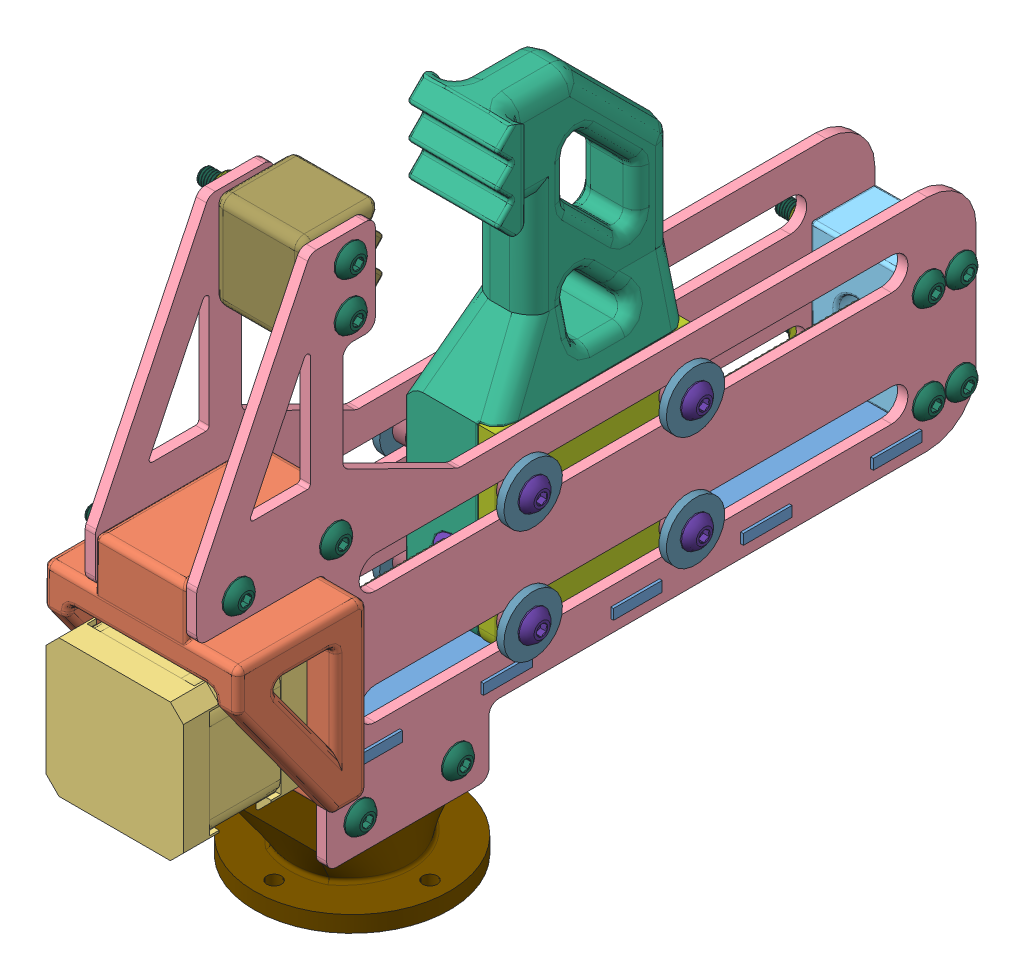
SolidWorks assembly UOM20-4A005, configuration Default. Lengths in mm.
Overall size (60 183.76 249.79).
68 component instances, 20 part files, 130 mates.
Components (placement in the parent):
- UOM20-4P007-1: UOM20-4P007 [Default] at (-2.435 1.3419 -83.2582) x (1 0 0) z (0 1 0) size (36 187.5 3.17)
- UOM20-4P033-1: UOM20-4P033 [Default] at (52.6461 0.8419 41.1062) x (-1 0 0) z (0 0 -1) size (60 68.5 50)
- Stepper with LeadScrew-1: Stepper with LeadScrew [Default] at (22.6461 22.5919 19.1062) x (1 0 0) z (0 1 0) size (42.3 239.5 42.3)
- UOM20-4P009-1: UOM20-4P009 [Default] at (39.8211 157.3419 -13.967) x (0 0 -1) z (1 0 0) size (240 167.68 3.17)
- UOM20-4P009-2: UOM20-4P009 [Default] at (8.6461 157.3419 -13.967) x (0 0 -1) z (1 0 0) size (240 167.68 3.17)
- UOM20-4P012-1: UOM20-4P012 [Default] at (8.6461 2.5919 -198.967) size (28 40 20)
- UOM20-4A006-1: UOM20-4A006 [Default] at (-25.0544 -2.4389 -59.9519) x (0 0 -1) z (1 0 0) size (60.07 140.34 28.19)
  - UOM20-4P011-1: UOM20-4P011 [Default] at (-5.5057 4.0308 33.7005) size (60.07 140.34 28.19)
  - UOM20-4P036-1: UOM20-4P036 [Default] at (54.4943 4.0308 61.7005) x (-1 0 0) z (0 0 -1) size (60 60 6)
  - 6659K676_OIL-EMBEDDED FLANGED SLEEVE BEARING-1: 6659K676_OIL-EMBEDDED FLANGED SLEEVE BEARING [6659K676] at (4.4943 25.0308 47.7005) x (0 -0.441612 0.897206) z (0 -0.897206 -0.441612) size (14 10 14)
  - 6659K676_OIL-EMBEDDED FLANGED SLEEVE BEARING-2: 6659K676_OIL-EMBEDDED FLANGED SLEEVE BEARING [6659K676] at (44.4943 25.0308 47.7005) x (0 -0.999819 0.019038) z (0 0.019038 0.999819) size (14 10 14)
  - 9434K135_MUSIC-WIRE STEEL COMPRESSION SPRINGS-1: 9434K135_MUSIC-WIRE STEEL COMPRESSION SPRINGS [9434K135] at (36.2443 25.1246 46.92) x (0 1 0) z (0 0 1) size (15.72 32.66 15.84)
  - leadnut-1: leadnut [Default] at (35.2443 25.0308 47.7005) x (1 0 0) z (0 0 -1) size (10 24 10.5)
  - UOM20-4P038-1: UOM20-4P038 [Default] at (43.2443 38.0308 55.7005) x (0 0 -1) z (-1 0 0) size (16 26 7)
- UOM20-4P008-1: UOM20-4P008 [Default] at (8.6461 111.8419 4.7646) x (0 0 -1) z (1 0 0) size (24.59 30 28)
- 94669A071_ALUM UNTHRD SPACER-1: 94669A071_ALUM UNTHRD SPACER [94669A071] at (38.6461 11.5919 -59.4462) x (0 0.521387 0.85332) z (1 0 0) size (10 10 4)
- 98363A111_ STEEL OVERSIZED WASHER-1: 98363A111_ STEEL OVERSIZED WASHER [98363A111] at (42.9461 11.5919 -59.4462) x (0 0.435821 0.900034) z (-1 0 0) size (18 18 2.3)
- 94669A071_ALUM UNTHRD SPACER-4: 94669A071_ALUM UNTHRD SPACER [94669A071] at (6.6461 11.5919 -59.4462) x (0 0.783153 0.621829) z (-1 0 0) size (10 10 4)
- 94669A071_ALUM UNTHRD SPACER-5: 94669A071_ALUM UNTHRD SPACER [94669A071] at (38.6461 46.5919 -109.4462) x (0 0.783153 0.621829) z (-1 0 0) size (10 10 4)
- 94669A071_ALUM UNTHRD SPACER-6: 94669A071_ALUM UNTHRD SPACER [94669A071] at (6.6461 46.5919 -59.4462) x (0 0.783153 0.621829) z (-1 0 0) size (10 10 4)
- 94669A071_ALUM UNTHRD SPACER-7: 94669A071_ALUM UNTHRD SPACER [94669A071] at (38.6461 11.5919 -109.4462) x (0 0.783153 0.621829) z (-1 0 0) size (10 10 4)
- 94669A071_ALUM UNTHRD SPACER-8: 94669A071_ALUM UNTHRD SPACER [94669A071] at (6.6461 11.5919 -109.4462) x (0 0.783153 0.621829) z (-1 0 0) size (10 10 4)
- 94669A071_ALUM UNTHRD SPACER-9: 94669A071_ALUM UNTHRD SPACER [94669A071] at (6.6461 46.5919 -109.4462) x (0 -0.340925 0.94009) z (-1 0 0) size (10 10 4)
- 94669A071_ALUM UNTHRD SPACER-10: 94669A071_ALUM UNTHRD SPACER [94669A071] at (38.6461 46.5919 -59.4462) x (0 0.783153 0.621829) z (-1 0 0) size (10 10 4)
- 98363A111_ STEEL OVERSIZED WASHER-2: 98363A111_ STEEL OVERSIZED WASHER [98363A111] at (42.9461 46.5919 -59.4462) x (0 0.435821 0.900034) z (-1 0 0) size (18 18 2.3)
- 98363A111_ STEEL OVERSIZED WASHER-3: 98363A111_ STEEL OVERSIZED WASHER [98363A111] at (42.9461 46.5919 -109.4462) x (0 0.435821 0.900034) z (-1 0 0) size (18 18 2.3)
- 98363A111_ STEEL OVERSIZED WASHER-4: 98363A111_ STEEL OVERSIZED WASHER [98363A111] at (42.9461 11.5919 -109.4462) x (0 0.603887 0.79707) z (-1 0 0) size (18 18 2.3)
- 98363A111_ STEEL OVERSIZED WASHER-5: 98363A111_ STEEL OVERSIZED WASHER [98363A111] at (4.6461 46.5919 -59.4462) x (0 0.435821 0.900034) z (-1 0 0) size (18 18 2.3)
- 98363A111_ STEEL OVERSIZED WASHER-6: 98363A111_ STEEL OVERSIZED WASHER [98363A111] at (4.6461 11.5919 -59.4462) x (0 0.435821 0.900034) z (-1 0 0) size (18 18 2.3)
- 98363A111_ STEEL OVERSIZED WASHER-7: 98363A111_ STEEL OVERSIZED WASHER [98363A111] at (4.6461 11.5919 -109.4462) x (0 0.756126 0.654426) z (-1 0 0) size (18 18 2.3)
- 98363A111_ STEEL OVERSIZED WASHER-8: 98363A111_ STEEL OVERSIZED WASHER [98363A111] at (4.6461 46.5919 -109.4462) x (0 0.435821 0.900034) z (-1 0 0) size (18 18 2.3)
- 92095A223_BUTTON HEAD HEX DRIVE SCREW (1)-1: 92095A223_BUTTON HEAD HEX DRIVE SCREW (1) [92095A223] at (42.5711 37.5919 -193.967) x (0 0.716827 -0.697251) z (1 0 0) size (9.5 9.5 48.41)
- 92095A223_BUTTON HEAD HEX DRIVE SCREW (1)-2: 92095A223_BUTTON HEAD HEX DRIVE SCREW (1) [92095A223] at (42.5711 37.5919 -183.967) x (0 0.158553 -0.987351) z (1 0 0) size (9.5 9.5 48.41)
- 92095A223_BUTTON HEAD HEX DRIVE SCREW (1)-3: 92095A223_BUTTON HEAD HEX DRIVE SCREW (1) [92095A223] at (42.5711 7.5919 -183.967) x (0 0.282984 -0.959125) z (1 0 0) size (9.5 9.5 48.41)
- 92095A223_BUTTON HEAD HEX DRIVE SCREW (1)-4: 92095A223_BUTTON HEAD HEX DRIVE SCREW (1) [92095A223] at (42.5711 7.5919 -193.967) x (0 0.371154 -0.928571) z (1 0 0) size (9.5 9.5 48.41)
- 93625A200_18-8 STAINLESS STEEL NYLON-INSERT LOCKNUT-14: 93625A200_18-8 STAINLESS STEEL NYLON-INSERT LOCKNUT [93625A200] at (2.9711 37.5919 -183.967) x (0 1 0) z (0 0 1) size (8 5.02 9.24)
- 93625A200_18-8 STAINLESS STEEL NYLON-INSERT LOCKNUT-17: 93625A200_18-8 STAINLESS STEEL NYLON-INSERT LOCKNUT [93625A200] at (2.9711 37.5919 -193.967) x (0 0.266649 0.963794) z (0 -0.963794 0.266649) size (8 5.02 9.24)
- 93625A200_18-8 STAINLESS STEEL NYLON-INSERT LOCKNUT-15: 93625A200_18-8 STAINLESS STEEL NYLON-INSERT LOCKNUT [93625A200] at (2.9711 7.5919 -183.967) x (0 -0.998058 -0.062298) z (0 0.062298 -0.998058) size (8 5.02 9.24)
- 93625A200_18-8 STAINLESS STEEL NYLON-INSERT LOCKNUT-23: 93625A200_18-8 STAINLESS STEEL NYLON-INSERT LOCKNUT [93625A200] at (2.9711 7.5919 -193.967) x (0 -0.998058 -0.062298) z (0 0.062298 -0.998058) size (8 5.02 9.24)
- 92095A223_BUTTON HEAD HEX DRIVE SCREW (1)-6: 92095A223_BUTTON HEAD HEX DRIVE SCREW (1) [92095A223] at (42.5711 119.3419 -5.967) x (0 0.158553 -0.987351) z (1 0 0) size (9.5 9.5 48.41)
- 92095A223_BUTTON HEAD HEX DRIVE SCREW (1)-8: 92095A223_BUTTON HEAD HEX DRIVE SCREW (1) [92095A223] at (42.5711 61.8419 -1.467) x (0 0.125077 -0.992147) z (1 0 0) size (9.5 9.5 48.41)
- 92095A223_BUTTON HEAD HEX DRIVE SCREW (1)-9: 92095A223_BUTTON HEAD HEX DRIVE SCREW (1) [92095A223] at (42.5711 134.3419 -5.967) x (0 0.431476 -0.902124) z (1 0 0) size (9.5 9.5 48.41)
- 92095A223_BUTTON HEAD HEX DRIVE SCREW (1)-10: 92095A223_BUTTON HEAD HEX DRIVE SCREW (1) [92095A223] at (42.5711 61.8419 28.533) x (0 0.513686 -0.857978) z (1 0 0) size (9.5 9.5 48.41)
- 92095A223_BUTTON HEAD HEX DRIVE SCREW (1)-11: 92095A223_BUTTON HEAD HEX DRIVE SCREW (1) [92095A223] at (42.5711 -15.8331 -38.967) x (0 0.559632 -0.828741) z (1 0 0) size (9.5 9.5 48.41)
- 92095A223_BUTTON HEAD HEX DRIVE SCREW (1)-13: 92095A223_BUTTON HEAD HEX DRIVE SCREW (1) [92095A223] at (42.5711 -15.8331 -8.967) x (0 0.683952 -0.729527) z (1 0 0) size (9.5 9.5 48.41)
- 93625A200_18-8 STAINLESS STEEL NYLON-INSERT LOCKNUT-20: 93625A200_18-8 STAINLESS STEEL NYLON-INSERT LOCKNUT [93625A200] at (2.9711 61.8419 28.533) x (0 0.266649 0.963794) z (0 -0.963794 0.266649) size (8 5.02 9.24)
- 93625A200_18-8 STAINLESS STEEL NYLON-INSERT LOCKNUT-16: 93625A200_18-8 STAINLESS STEEL NYLON-INSERT LOCKNUT [93625A200] at (2.9711 -15.8331 -8.967) x (0 0.110464 0.99388) z (0 -0.99388 0.110464) size (8 5.02 9.24)
- 93625A200_18-8 STAINLESS STEEL NYLON-INSERT LOCKNUT-24: 93625A200_18-8 STAINLESS STEEL NYLON-INSERT LOCKNUT [93625A200] at (2.9711 134.3419 -5.967) x (0 -0.016988 0.999856) z (0 -0.999856 -0.016988) size (8 5.02 9.24)
- 93625A200_18-8 STAINLESS STEEL NYLON-INSERT LOCKNUT-18: 93625A200_18-8 STAINLESS STEEL NYLON-INSERT LOCKNUT [93625A200] at (2.9711 -15.8331 -38.967) x (0 -0.311672 0.95019) z (0 -0.95019 -0.311672) size (8 5.02 9.24)
- 93625A200_18-8 STAINLESS STEEL NYLON-INSERT LOCKNUT-25: 93625A200_18-8 STAINLESS STEEL NYLON-INSERT LOCKNUT [93625A200] at (2.9711 61.8419 -1.467) x (0 0.201211 -0.979548) z (0 0.979548 0.201211) size (8 5.02 9.24)
- 93625A200_18-8 STAINLESS STEEL NYLON-INSERT LOCKNUT-26: 93625A200_18-8 STAINLESS STEEL NYLON-INSERT LOCKNUT [93625A200] at (2.9711 119.3419 -5.967) x (0 -0.173645 0.984808) z (0 -0.984808 -0.173645) size (8 5.02 9.24)
- 93625A200_18-8 STAINLESS STEEL NYLON-INSERT LOCKNUT-19: 93625A200_18-8 STAINLESS STEEL NYLON-INSERT LOCKNUT [93625A200] at (-0.1539 11.5919 -109.4462) x (0 -0.311672 0.95019) z (0 -0.95019 -0.311672) size (8 5.02 9.24)
- 93625A200_18-8 STAINLESS STEEL NYLON-INSERT LOCKNUT-13: 93625A200_18-8 STAINLESS STEEL NYLON-INSERT LOCKNUT [93625A200] at (-0.1539 11.5919 -59.4462) x (0 -0.458385 0.888754) z (0 -0.888754 -0.458385) size (8 5.02 9.24)
- 93625A200_18-8 STAINLESS STEEL NYLON-INSERT LOCKNUT-21: 93625A200_18-8 STAINLESS STEEL NYLON-INSERT LOCKNUT [93625A200] at (-0.1539 46.5919 -109.4462) x (0 -0.56782 0.823153) z (0 -0.823153 -0.56782) size (8 5.02 9.24)
- 93625A200_18-8 STAINLESS STEEL NYLON-INSERT LOCKNUT-22: 93625A200_18-8 STAINLESS STEEL NYLON-INSERT LOCKNUT [93625A200] at (-0.1539 46.5919 -59.4462) x (0 -0.642076 0.766641) z (0 -0.766641 -0.642076) size (8 5.02 9.24)
- 92095A228_BUTTON HEAD HEX DRIVE SCREW-1: 92095A228_BUTTON HEAD HEX DRIVE SCREW [92095A228] at (45.6961 11.5919 -59.4462) x (0 -0.924225 -0.381849) z (1 0 0) size (9.5 9.5 53.02)
- 92095A228_BUTTON HEAD HEX DRIVE SCREW-2: 92095A228_BUTTON HEAD HEX DRIVE SCREW [92095A228] at (45.6961 46.5919 -59.4462) x (0 0 -1) z (1 0 0) size (9.5 9.5 53.02)
- 92095A228_BUTTON HEAD HEX DRIVE SCREW-3: 92095A228_BUTTON HEAD HEX DRIVE SCREW [92095A228] at (45.6961 46.5919 -109.4462) x (0 0 -1) z (1 0 0) size (9.5 9.5 53.02)
- 92095A228_BUTTON HEAD HEX DRIVE SCREW-4: 92095A228_BUTTON HEAD HEX DRIVE SCREW [92095A228] at (45.6961 11.5919 -109.4462) x (0 0 -1) z (1 0 0) size (9.5 9.5 53.02)
- UOM20-4P013-2: UOM20-4P013 [Default] at (22.6461 -36.8331 -23.967) x (0 0 1) z (0 1 0) size (60 60 40)
- 92855A313_TYPE 18-8 SS LOW PROFILE SOCKET CAP SCREW-1: 92855A313_TYPE 18-8 SS LOW PROFILE SOCKET CAP SCREW [92855A313] at (38.1461 38.0919 15.5062) size (5.5 5.5 14.55)
- 98689A112_ METRIC GENERAL PURPOSE WASHERS (1)-1: 98689A112_ METRIC GENERAL PURPOSE WASHERS (1) [98689A112] at (38.1461 38.0919 4.1062) x (-0.923728 -0.383049 0) z (0 0 -1) size (6 6 0.6)
- 98689A112_ METRIC GENERAL PURPOSE WASHERS (1)-2: 98689A112_ METRIC GENERAL PURPOSE WASHERS (1) [98689A112] at (38.1461 7.0919 4.1062) x (-0.85131 -0.524663 0) z (0 0 -1) size (6 6 0.6)
- 98689A112_ METRIC GENERAL PURPOSE WASHERS (1)-4: 98689A112_ METRIC GENERAL PURPOSE WASHERS (1) [98689A112] at (7.1461 7.0919 4.1062) x (-0.777574 -0.628792 0) z (0 0 -1) size (6 6 0.6)
- 98689A112_ METRIC GENERAL PURPOSE WASHERS (1)-6: 98689A112_ METRIC GENERAL PURPOSE WASHERS (1) [98689A112] at (7.1461 38.0919 4.1062) x (-0.715577 -0.698533 0) z (0 0 -1) size (6 6 0.6)
- 92855A313_TYPE 18-8 SS LOW PROFILE SOCKET CAP SCREW-3: 92855A313_TYPE 18-8 SS LOW PROFILE SOCKET CAP SCREW [92855A313] at (38.1461 7.0919 15.5062) x (0.216826 -0.97621 0) z (0 0 1) size (5.5 5.5 14.55)
- 92855A313_TYPE 18-8 SS LOW PROFILE SOCKET CAP SCREW-5: 92855A313_TYPE 18-8 SS LOW PROFILE SOCKET CAP SCREW [92855A313] at (7.1461 7.0919 15.5062) x (0.044015 -0.999031 0) z (0 0 1) size (5.5 5.5 14.55)
- 92855A313_TYPE 18-8 SS LOW PROFILE SOCKET CAP SCREW-7: 92855A313_TYPE 18-8 SS LOW PROFILE SOCKET CAP SCREW [92855A313] at (7.1461 38.0919 15.5062) x (-0.130134 -0.991496 0) z (0 0 1) size (5.5 5.5 14.55)
Mates (geometry in assembly coordinates):
- Concentric3: concentric anti-aligned: circle of Part4-1; circle of Stepper with LeadScrew-1
- Coincident3: coincident anti-aligned: plane of Part4-1 through (52.6461 0.8419 11.1062) normal (0 0 1); plane of Stepper with LeadScrew-1 through (22.6461 22.5919 11.1062) normal (0 0 -1)
- Parallel1: parallel aligned: plane of Part4-1 through (-7.3539 40.8419 1.1062) normal (-1 0 0); plane of Stepper with LeadScrew-1 through (1.5461 37.4919 41.1062) normal (-1 0 0)
- Parallel2: parallel anti-aligned: plane of Part1-1 through (-2.435 -1.8331 -83.2582) normal (0 -1 0); plane of Part4-1 through (8.6461 69.3419 41.033) normal (0 1 0)
- Coincident7: coincident aligned: plane of Part1-1 through (8.6461 -8.6581 18.533) normal (-1 0 0); plane of Part4-1 through (8.6461 0.8419 41.1062) normal (-1 0 0)
- Coincident8: coincident anti-aligned: plane of UOM20-4P031-1 through (40.6461 -8.6581 -6.467) normal (0 0 1); plane of UOM20-4P032-1 through (36.6461 -1.8331 -6.467) normal (0 0 -1)
- Coincident9: coincident anti-aligned: plane of Part2-1 through (36.6461 157.3419 -13.967) normal (-1 0 0); plane of Part4-1 through (36.6461 0.8419 41.1062) normal (1 0 0)
- Coincident10: coincident anti-aligned: plane of Part1-1 through (-2.435 1.3419 -83.2582) normal (0 1 0); plane of Part2-1 through (36.6461 1.3419 -101.467) normal (0 -1 0)
- Coincident19: coincident anti-aligned: plane of Part4-1 through (-7.3539 54.3419 1.1062) normal (0 1 0); plane of Part2-1 through (36.6461 54.3419 41.033) normal (0 -1 0)
- Coincident24: coincident anti-aligned: plane of Part4-1 through (8.6461 0.8419 41.1062) normal (-1 0 0); plane of Part2-2 through (8.6461 157.3419 -13.967) normal (1 0 0)
- Coincident25: coincident aligned: plane of UOM20-4P032-1 through (36.6461 61.8419 -198.967) normal (0 0 -1); plane of UOM20-4P032-2 through (5.4711 61.8419 -198.967) normal (0 0 -1)
- Concentric4: concentric aligned: cylinder of Part4-1 through (22.6461 22.5919 1.1062) axis (0 0 1) radius 14; cylinder of UOM20-4P034-1 through (22.6461 22.5919 -190.967) axis (0 0 1) radius 6
- Coincident27: coincident aligned: plane of UOM20-4P032-2 through (5.4711 61.8419 -198.967) normal (0 0 -1); plane of UOM20-4P034-1 through (8.6461 2.5919 -198.967) normal (0 0 -1)
- Coincident28: coincident anti-aligned: plane of Part1-1 through (-2.435 -1.8331 -83.2582) normal (0 -1 0); plane of Part2-2 through (5.4711 -1.8331 -166.467) normal (0 1 0)
- Concentric5: concentric anti-aligned: cylinder of Part4-1 through (22.6461 22.5919 1.1062) axis (0 0 1) radius 14; cylinder of UOM20-4A006-1/UOM20-4P035-1 through (22.6461 22.5919 -54.4462) axis (0 0 -1) radius 5.515
- Coincident29: coincident anti-aligned: plane of Part2-2 through (8.6461 157.3419 -13.967) normal (1 0 0); plane of UOM20-4A006-1/UOM20-4P035-1 through (8.6461 1.5919 -54.4462) normal (-1 0 0)
- Coincident30: coincident anti-aligned: plane of Part2-2 through (8.6461 157.3419 -13.967) normal (1 0 0); plane of top finger-1 through (8.6461 111.8419 4.7646) normal (-1 0 0)
- Coincident32: coincident: line of Part2-1 through (39.8211 141.8419 4.15) axis (0 0 -1); plane of top finger-1 through (36.6461 141.8419 4.7646) normal (0 1 0)
- Coincident33: coincident aligned: circle of Part2-1; cylinder of UOM20-4P037-1 through (8.6461 134.3419 -5.967) axis (1 0 0) radius 2.5
- Concentric13: concentric anti-aligned: cylinder of UOM20-4A006-1/UOM20-4P035-1 through (30.6461 11.5919 -59.4462) axis (1 0 0) radius 2.5; cylinder of 94669A071_ALUM UNTHRD SPACER-1 through (40.6461 11.5919 -59.4462) axis (-1 0 0) radius 2.65
- Coincident37: coincident anti-aligned: plane of UOM20-4A006-1/UOM20-4P036-1 through (36.6461 1.5919 -114.4462) normal (1 0 0); plane of 94669A071_ALUM UNTHRD SPACER-1 through (36.6461 11.5919 -59.4462) normal (-1 0 0)
- Coincident39: coincident anti-aligned: plane of 94669A071_ALUM UNTHRD SPACER-1 through (40.6461 11.5919 -59.4462) normal (1 0 0); plane of 98363A111_ STEEL OVERSIZED WASHER-1 through (40.6461 11.5919 -59.4462) normal (-1 0 0)
- Concentric15: concentric anti-aligned: cylinder of 94669A071_ALUM UNTHRD SPACER-1 through (40.6461 11.5919 -59.4462) axis (-1 0 0) radius 5; cylinder of 98363A111_ STEEL OVERSIZED WASHER-1 through (40.6461 11.5919 -59.4462) axis (1 0 0) radius 9
- Concentric17: concentric anti-aligned: cylinder of UOM20-4A006-1/UOM20-4P036-1 through (30.6461 46.5919 -109.4462) axis (-1 0 0) radius 2.5; cylinder of 94669A071_ALUM UNTHRD SPACER-9 through (4.6461 46.5919 -109.4462) axis (1 0 0) radius 2.65
- Concentric18: concentric anti-aligned: cylinder of UOM20-4A006-1/UOM20-4P036-1 through (30.6461 11.5919 -109.4462) axis (-1 0 0) radius 2.5; cylinder of 94669A071_ALUM UNTHRD SPACER-8 through (4.6461 11.5919 -109.4462) axis (1 0 0) radius 2.65
- Concentric19: concentric anti-aligned: cylinder of UOM20-4A006-1/UOM20-4P036-1 through (30.6461 46.5919 -59.4462) axis (-1 0 0) radius 2.5; cylinder of 94669A071_ALUM UNTHRD SPACER-6 through (4.6461 46.5919 -59.4462) axis (1 0 0) radius 2.65
- Coincident43: coincident aligned: plane of 94669A071_ALUM UNTHRD SPACER-8 through (8.6461 11.5919 -109.4462) normal (1 0 0); plane of 94669A071_ALUM UNTHRD SPACER-9 through (8.6461 46.5919 -109.4462) normal (1 0 0)
- Coincident44: coincident aligned: plane of 94669A071_ALUM UNTHRD SPACER-6 through (8.6461 46.5919 -59.4462) normal (1 0 0); plane of 94669A071_ALUM UNTHRD SPACER-9 through (8.6461 46.5919 -109.4462) normal (1 0 0)
- Coincident45: coincident anti-aligned: plane of UOM20-4A006-1/UOM20-4P035-1 through (8.6461 1.5919 -54.4462) normal (-1 0 0); plane of 94669A071_ALUM UNTHRD SPACER-9 through (8.6461 46.5919 -109.4462) normal (1 0 0)
- Coincident46: coincident anti-aligned: plane of UOM20-4A006-1/UOM20-4P035-1 through (8.6461 1.5919 -54.4462) normal (-1 0 0); plane of 94669A071_ALUM UNTHRD SPACER-4 through (8.6461 11.5919 -59.4462) normal (1 0 0)
- Concentric20: concentric anti-aligned: cylinder of 94669A071_ALUM UNTHRD SPACER-1 through (40.6461 11.5919 -59.4462) axis (-1 0 0) radius 5; cylinder of 94669A071_ALUM UNTHRD SPACER-4 through (4.6461 11.5919 -59.4462) axis (1 0 0) radius 2.65
- Coincident47: coincident aligned: plane of 94669A071_ALUM UNTHRD SPACER-5 through (36.6461 46.5919 -109.4462) normal (-1 0 0); plane of 94669A071_ALUM UNTHRD SPACER-7 through (36.6461 11.5919 -109.4462) normal (-1 0 0)
- Coincident48: coincident aligned: plane of 94669A071_ALUM UNTHRD SPACER-5 through (36.6461 46.5919 -109.4462) normal (-1 0 0); plane of 94669A071_ALUM UNTHRD SPACER-10 through (36.6461 46.5919 -59.4462) normal (-1 0 0)
- Coincident49: coincident anti-aligned: plane of UOM20-4A006-1/UOM20-4P036-1 through (36.6461 1.5919 -114.4462) normal (1 0 0); plane of 94669A071_ALUM UNTHRD SPACER-10 through (36.6461 46.5919 -59.4462) normal (-1 0 0)
- Concentric21: concentric aligned: circle of 94669A071_ALUM UNTHRD SPACER-5; circle of UOM20-4A006-1/UOM20-4P036-1
- Concentric22: concentric aligned: circle of 94669A071_ALUM UNTHRD SPACER-10; circle of UOM20-4A006-1/UOM20-4P036-1
- Concentric23: concentric aligned: circle of 94669A071_ALUM UNTHRD SPACER-7; circle of UOM20-4A006-1/UOM20-4P036-1
- Coincident50: coincident anti-aligned: circle of 98363A111_ STEEL OVERSIZED WASHER-1; plane of 98363A111_ STEEL OVERSIZED WASHER-2 through (42.9461 46.5919 -59.4462) normal (1 0 0)
- Coincident51: coincident anti-aligned: circle of 98363A111_ STEEL OVERSIZED WASHER-1; plane of 98363A111_ STEEL OVERSIZED WASHER-3 through (42.9461 46.5919 -109.4462) normal (1 0 0)
- Coincident52: coincident anti-aligned: circle of 98363A111_ STEEL OVERSIZED WASHER-1; plane of 98363A111_ STEEL OVERSIZED WASHER-4 through (42.9461 11.5919 -109.4462) normal (1 0 0)
- Concentric24: concentric anti-aligned: cylinder of 94669A071_ALUM UNTHRD SPACER-10 through (36.6461 46.5919 -59.4462) axis (1 0 0) radius 2.65; circle of 98363A111_ STEEL OVERSIZED WASHER-2
- Concentric25: concentric aligned: cylinder of 94669A071_ALUM UNTHRD SPACER-5 through (36.6461 46.5919 -109.4462) axis (1 0 0) radius 2.65; cylinder of 98363A111_ STEEL OVERSIZED WASHER-3 through (40.6461 46.5919 -109.4462) axis (1 0 0) radius 2.75
- Concentric26: concentric aligned: cylinder of 94669A071_ALUM UNTHRD SPACER-7 through (36.6461 11.5919 -109.4462) axis (1 0 0) radius 2.65; cylinder of 98363A111_ STEEL OVERSIZED WASHER-4 through (40.6461 11.5919 -109.4462) axis (1 0 0) radius 2.75
- Coincident57: coincident aligned: plane of 98363A111_ STEEL OVERSIZED WASHER-6 through (4.6461 11.5919 -59.4462) normal (1 0 0); plane of 98363A111_ STEEL OVERSIZED WASHER-7 through (4.6461 11.5919 -109.4462) normal (1 0 0)
- Coincident58: coincident aligned: plane of 98363A111_ STEEL OVERSIZED WASHER-5 through (4.6461 46.5919 -59.4462) normal (1 0 0); plane of 98363A111_ STEEL OVERSIZED WASHER-8 through (4.6461 46.5919 -109.4462) normal (1 0 0)
- Coincident59: coincident aligned: plane of 98363A111_ STEEL OVERSIZED WASHER-6 through (4.6461 11.5919 -59.4462) normal (1 0 0); plane of 98363A111_ STEEL OVERSIZED WASHER-8 through (4.6461 46.5919 -109.4462) normal (1 0 0)
- Coincident60: coincident anti-aligned: plane of 94669A071_ALUM UNTHRD SPACER-9 through (4.6461 46.5919 -109.4462) normal (-1 0 0); plane of 98363A111_ STEEL OVERSIZED WASHER-5 through (4.6461 46.5919 -59.4462) normal (1 0 0)
- Concentric30: concentric aligned: cylinder of 94669A071_ALUM UNTHRD SPACER-6 through (4.6461 46.5919 -59.4462) axis (1 0 0) radius 5; cylinder of 98363A111_ STEEL OVERSIZED WASHER-5 through (2.3461 46.5919 -59.4462) axis (1 0 0) radius 2.75
- Concentric31: concentric aligned: circle of 94669A071_ALUM UNTHRD SPACER-9; circle of 98363A111_ STEEL OVERSIZED WASHER-8
- Concentric32: concentric aligned: circle of 94669A071_ALUM UNTHRD SPACER-8; circle of 98363A111_ STEEL OVERSIZED WASHER-7
- Concentric33: concentric aligned: circle of 94669A071_ALUM UNTHRD SPACER-4; circle of 98363A111_ STEEL OVERSIZED WASHER-6
- Coincident70: coincident anti-aligned: plane of UOM20-4P032-1 through (36.6461 157.3419 -13.967) normal (-1 0 0); plane of UOM20-4P034-1 through (36.6461 2.5919 -178.967) normal (1 0 0)
- Coincident71: coincident anti-aligned: plane of UOM20-4P032-1 through (39.8211 157.3419 -13.967) normal (1 0 0); plane of 92095A223_BUTTON HEAD HEX DRIVE SCREW (1)-1 through (39.8211 34.2799 -197.372) normal (-1 0 0)
- Coincident72: coincident anti-aligned: plane of UOM20-4P032-1 through (39.8211 157.3419 -13.967) normal (1 0 0); plane of 92095A223_BUTTON HEAD HEX DRIVE SCREW (1)-2 through (39.8211 32.902 -184.7202) normal (-1 0 0)
- Coincident73: coincident anti-aligned: plane of UOM20-4P032-1 through (39.8211 157.3419 -13.967) normal (1 0 0); plane of 92095A223_BUTTON HEAD HEX DRIVE SCREW (1)-3 through (39.8211 3.036 -185.3112) normal (-1 0 0)
- Coincident74: coincident anti-aligned: plane of UOM20-4P032-1 through (39.8211 157.3419 -13.967) normal (1 0 0); plane of 92095A223_BUTTON HEAD HEX DRIVE SCREW (1)-4 through (39.8211 3.1812 -195.73) normal (-1 0 0)
- Concentric48: concentric aligned: cylinder of UOM20-4P034-1 through (8.6461 37.5919 -193.967) axis (1 0 0) radius 2.5; circle of 92095A223_BUTTON HEAD HEX DRIVE SCREW (1)-1
- Concentric49: concentric aligned: cylinder of UOM20-4P034-1 through (8.6461 37.5919 -183.967) axis (1 0 0) radius 2.5; circle of 92095A223_BUTTON HEAD HEX DRIVE SCREW (1)-2
- Concentric50: concentric aligned: cylinder of UOM20-4P034-1 through (8.6461 7.5919 -183.967) axis (1 0 0) radius 2.5; circle of 92095A223_BUTTON HEAD HEX DRIVE SCREW (1)-3
- Concentric51: concentric aligned: cylinder of UOM20-4P034-1 through (8.6461 7.5919 -193.967) axis (1 0 0) radius 2.5; circle of 92095A223_BUTTON HEAD HEX DRIVE SCREW (1)-4
- Coincident76: coincident anti-aligned: plane of UOM20-4P032-2 through (5.4711 157.3419 -13.967) normal (-1 0 0); plane of 93625A200_18-8 STAINLESS STEEL NYLON-INSERT LOCKNUT-17 through (5.4711 37.5919 -193.967) normal (1 0 0)
- Concentric52: concentric anti-aligned: circle of 92095A223_BUTTON HEAD HEX DRIVE SCREW (1)-1; circle of 94645A102_HIGH-STRENGTH STEEL NYLON-INSERT LOCKNUT-2
- Coincident77: coincident anti-aligned: plane of UOM20-4P009-2 through (5.4711 157.3419 -13.967) normal (-1 0 0); plane of 93625A200_18-8 STAINLESS STEEL NYLON-INSERT LOCKNUT-14 through (5.4711 37.5919 -183.967) normal (1 0 0)
- Concentric53: concentric anti-aligned: circle of 92095A223_BUTTON HEAD HEX DRIVE SCREW (1)-2; cylinder of 93625A200_18-8 STAINLESS STEEL NYLON-INSERT LOCKNUT-14 through (2.9711 37.5919 -183.967) axis (1 0 0) radius 2
- Coincident78: coincident anti-aligned: plane of UOM20-4P032-2 through (5.4711 157.3419 -13.967) normal (-1 0 0); plane of 93625A200_18-8 STAINLESS STEEL NYLON-INSERT LOCKNUT-15 through (5.4711 7.5919 -183.967) normal (1 0 0)
- Concentric54: concentric anti-aligned: circle of 92095A223_BUTTON HEAD HEX DRIVE SCREW (1)-3; circle of 94645A102_HIGH-STRENGTH STEEL NYLON-INSERT LOCKNUT-3
- Concentric55: concentric anti-aligned: circle of 92095A223_BUTTON HEAD HEX DRIVE SCREW (1)-4; circle of 94645A102_HIGH-STRENGTH STEEL NYLON-INSERT LOCKNUT-4
- Coincident79: coincident anti-aligned: plane of UOM20-4P032-2 through (5.4711 157.3419 -13.967) normal (-1 0 0); plane of 93625A200_18-8 STAINLESS STEEL NYLON-INSERT LOCKNUT-23 through (5.4711 7.5919 -193.967) normal (1 0 0)
- Coincident80: coincident anti-aligned: plane of UOM20-4P032-1 through (39.8211 157.3419 -13.967) normal (1 0 0); plane of 92095A223_BUTTON HEAD HEX DRIVE SCREW (1)-6 through (39.8211 114.652 -6.7202) normal (-1 0 0)
- Coincident81: coincident anti-aligned: plane of UOM20-4P032-1 through (39.8211 157.3419 -13.967) normal (1 0 0); plane of 92095A223_BUTTON HEAD HEX DRIVE SCREW (1)-8 through (39.8211 57.1292 -2.0611) normal (-1 0 0)
- Coincident82: coincident anti-aligned: plane of UOM20-4P032-1 through (39.8211 157.3419 -13.967) normal (1 0 0); plane of 92095A223_BUTTON HEAD HEX DRIVE SCREW (1)-9 through (39.8211 130.0568 -8.0165) normal (-1 0 0)
- Coincident83: coincident anti-aligned: plane of UOM20-4P032-1 through (39.8211 157.3419 -13.967) normal (1 0 0); plane of 92095A223_BUTTON HEAD HEX DRIVE SCREW (1)-10 through (39.8211 57.7665 26.093) normal (-1 0 0)
- Coincident84: coincident anti-aligned: plane of UOM20-4P032-1 through (39.8211 157.3419 -13.967) normal (1 0 0); plane of 92095A223_BUTTON HEAD HEX DRIVE SCREW (1)-11 through (39.8211 -19.7696 -41.6253) normal (-1 0 0)
- Concentric56: concentric aligned: cylinder of UOM20-4P032-1 through (29.8211 134.3419 -5.967) axis (1 0 0) radius 2.5; circle of 92095A223_BUTTON HEAD HEX DRIVE SCREW (1)-9
- Concentric57: concentric aligned: cylinder of UOM20-4P032-1 through (29.8211 119.3419 -5.967) axis (1 0 0) radius 2.5; circle of 92095A223_BUTTON HEAD HEX DRIVE SCREW (1)-6
- Concentric58: concentric aligned: cylinder of UOM20-4P032-1 through (36.6461 61.8419 -1.467) axis (1 0 0) radius 2.5; circle of 92095A223_BUTTON HEAD HEX DRIVE SCREW (1)-8
- Concentric59: concentric aligned: cylinder of UOM20-4P032-1 through (36.6461 61.8419 28.533) axis (1 0 0) radius 2.5; circle of 92095A223_BUTTON HEAD HEX DRIVE SCREW (1)-10
- Coincident87: coincident anti-aligned: plane of UOM20-4P032-1 through (39.8211 157.3419 -13.967) normal (1 0 0); plane of 92095A223_BUTTON HEAD HEX DRIVE SCREW (1)-13 through (39.8211 -19.2984 -12.2158) normal (-1 0 0)
- Concentric60: concentric aligned: cylinder of UOM20-4P032-1 through (36.6461 -15.8331 -38.967) axis (1 0 0) radius 3; circle of 92095A223_BUTTON HEAD HEX DRIVE SCREW (1)-11
- Concentric61: concentric aligned: cylinder of UOM20-4P032-1 through (36.6461 -15.8331 -8.967) axis (1 0 0) radius 3; circle of 92095A223_BUTTON HEAD HEX DRIVE SCREW (1)-13
- Concentric62: concentric aligned: cylinder of UOM20-4P033-1 through (-7.3539 61.8419 28.533) axis (1 0 0) radius 2.5; cylinder of UOM20-4P032-1 through (36.6461 61.8419 28.533) axis (1 0 0) radius 2.5
- Coincident89: coincident anti-aligned: plane of UOM20-4P032-2 through (5.4711 157.3419 -13.967) normal (-1 0 0); plane of 93625A200_18-8 STAINLESS STEEL NYLON-INSERT LOCKNUT-20 through (5.4711 61.8419 28.533) normal (1 0 0)
- Coincident90: coincident anti-aligned: plane of UOM20-4P032-2 through (5.4711 157.3419 -13.967) normal (-1 0 0); plane of 93625A200_18-8 STAINLESS STEEL NYLON-INSERT LOCKNUT-16 through (5.4711 -15.8331 -8.967) normal (1 0 0)
- Coincident91: coincident anti-aligned: plane of UOM20-4P032-2 through (5.4711 157.3419 -13.967) normal (-1 0 0); plane of 93625A200_18-8 STAINLESS STEEL NYLON-INSERT LOCKNUT-24 through (5.4711 134.3419 -5.967) normal (1 0 0)
- Coincident92: coincident anti-aligned: plane of UOM20-4P032-2 through (5.4711 157.3419 -13.967) normal (-1 0 0); plane of 93625A200_18-8 STAINLESS STEEL NYLON-INSERT LOCKNUT-18 through (5.4711 -15.8331 -38.967) normal (1 0 0)
- Coincident93: coincident anti-aligned: plane of UOM20-4P032-2 through (5.4711 157.3419 -13.967) normal (-1 0 0); plane of 93625A200_18-8 STAINLESS STEEL NYLON-INSERT LOCKNUT-25 through (5.4711 61.8419 -1.467) normal (1 0 0)
- Coincident94: coincident anti-aligned: plane of UOM20-4P032-2 through (5.4711 157.3419 -13.967) normal (-1 0 0); plane of 93625A200_18-8 STAINLESS STEEL NYLON-INSERT LOCKNUT-26 through (5.4711 119.3419 -5.967) normal (1 0 0)
- Concentric63: concentric anti-aligned: circle of 92095A223_BUTTON HEAD HEX DRIVE SCREW (1)-9; cylinder of 93625A200_18-8 STAINLESS STEEL NYLON-INSERT LOCKNUT-24 through (2.9711 134.3419 -5.967) axis (1 0 0) radius 2
- Concentric64: concentric anti-aligned: circle of 92095A223_BUTTON HEAD HEX DRIVE SCREW (1)-6; circle of 94645A102_HIGH-STRENGTH STEEL NYLON-INSERT LOCKNUT-10
- Concentric65: concentric anti-aligned: circle of 92095A223_BUTTON HEAD HEX DRIVE SCREW (1)-8; cylinder of 93625A200_18-8 STAINLESS STEEL NYLON-INSERT LOCKNUT-25 through (2.9711 61.8419 -1.467) axis (1 0 0) radius 2
- Concentric66: concentric anti-aligned: circle of 92095A223_BUTTON HEAD HEX DRIVE SCREW (1)-10; cylinder of 93625A200_18-8 STAINLESS STEEL NYLON-INSERT LOCKNUT-20 through (2.9711 61.8419 28.533) axis (1 0 0) radius 2
- Concentric67: concentric anti-aligned: circle of 92095A223_BUTTON HEAD HEX DRIVE SCREW (1)-11; cylinder of 93625A200_18-8 STAINLESS STEEL NYLON-INSERT LOCKNUT-18 through (2.9711 -15.8331 -38.967) axis (1 0 0) radius 2
- Concentric68: concentric anti-aligned: circle of 92095A223_BUTTON HEAD HEX DRIVE SCREW (1)-13; cylinder of 93625A200_18-8 STAINLESS STEEL NYLON-INSERT LOCKNUT-16 through (2.9711 -15.8331 -8.967) axis (1 0 0) radius 2
- Coincident96: coincident anti-aligned: plane of 98363A111_ STEEL OVERSIZED WASHER-7 through (2.3461 11.5919 -109.4462) normal (-1 0 0); plane of 93625A200_18-8 STAINLESS STEEL NYLON-INSERT LOCKNUT-19 through (2.3461 11.5919 -109.4462) normal (1 0 0)
- Coincident97: coincident anti-aligned: plane of 98363A111_ STEEL OVERSIZED WASHER-7 through (2.3461 11.5919 -109.4462) normal (-1 0 0); plane of 93625A200_18-8 STAINLESS STEEL NYLON-INSERT LOCKNUT-13 through (2.3461 11.5919 -59.4462) normal (1 0 0)
- Coincident98: coincident anti-aligned: plane of 98363A111_ STEEL OVERSIZED WASHER-7 through (2.3461 11.5919 -109.4462) normal (-1 0 0); plane of 93625A200_18-8 STAINLESS STEEL NYLON-INSERT LOCKNUT-21 through (2.3461 46.5919 -109.4462) normal (1 0 0)
- Coincident99: coincident anti-aligned: plane of 98363A111_ STEEL OVERSIZED WASHER-7 through (2.3461 11.5919 -109.4462) normal (-1 0 0); plane of 93625A200_18-8 STAINLESS STEEL NYLON-INSERT LOCKNUT-22 through (2.3461 46.5919 -59.4462) normal (1 0 0)
- Coincident101: coincident aligned: plane of 98363A111_ STEEL OVERSIZED WASHER-1 through (42.9461 11.5919 -59.4462) normal (1 0 0); circle of 92095A228_BUTTON HEAD HEX DRIVE SCREW-1
- Coincident102: coincident anti-aligned: plane of 98363A111_ STEEL OVERSIZED WASHER-2 through (42.9461 46.5919 -59.4462) normal (1 0 0); plane of 92095A228_BUTTON HEAD HEX DRIVE SCREW-2 through (42.9461 41.8419 -59.4462) normal (-1 0 0)
- Coincident103: coincident anti-aligned: plane of 98363A111_ STEEL OVERSIZED WASHER-3 through (42.9461 46.5919 -109.4462) normal (1 0 0); plane of 92095A228_BUTTON HEAD HEX DRIVE SCREW-3 through (42.9461 41.8419 -109.4462) normal (-1 0 0)
- Coincident104: coincident anti-aligned: plane of 98363A111_ STEEL OVERSIZED WASHER-4 through (42.9461 11.5919 -109.4462) normal (1 0 0); plane of 92095A228_BUTTON HEAD HEX DRIVE SCREW-4 through (42.9461 6.8419 -109.4462) normal (-1 0 0)
- Concentric73: concentric aligned: cylinder of 98363A111_ STEEL OVERSIZED WASHER-2 through (40.6461 46.5919 -59.4462) axis (1 0 0) radius 2.75; circle of 92095A228_BUTTON HEAD HEX DRIVE SCREW-2
- Concentric74: concentric aligned: cylinder of 98363A111_ STEEL OVERSIZED WASHER-3 through (40.6461 46.5919 -109.4462) axis (1 0 0) radius 2.75; circle of 92095A228_BUTTON HEAD HEX DRIVE SCREW-3
- Concentric75: concentric aligned: cylinder of 98363A111_ STEEL OVERSIZED WASHER-4 through (40.6461 11.5919 -109.4462) axis (1 0 0) radius 2.75; circle of 92095A228_BUTTON HEAD HEX DRIVE SCREW-4
- Concentric76: concentric aligned: cylinder of 98363A111_ STEEL OVERSIZED WASHER-1 through (40.6461 11.5919 -59.4462) axis (1 0 0) radius 2.75; circle of 92095A228_BUTTON HEAD HEX DRIVE SCREW-1
- Concentric77: concentric anti-aligned: circle of 92095A228_BUTTON HEAD HEX DRIVE SCREW-3; cylinder of 93625A200_18-8 STAINLESS STEEL NYLON-INSERT LOCKNUT-21 through (-0.1539 46.5919 -109.4462) axis (1 0 0) radius 2
- Concentric78: concentric anti-aligned: circle of 92095A228_BUTTON HEAD HEX DRIVE SCREW-2; cylinder of 93625A200_18-8 STAINLESS STEEL NYLON-INSERT LOCKNUT-22 through (-0.1539 46.5919 -59.4462) axis (1 0 0) radius 2
- Concentric79: concentric anti-aligned: circle of 92095A228_BUTTON HEAD HEX DRIVE SCREW-1; cylinder of 93625A200_18-8 STAINLESS STEEL NYLON-INSERT LOCKNUT-13 through (-0.1539 11.5919 -59.4462) axis (1 0 0) radius 2
- Concentric80: concentric anti-aligned: circle of 92095A228_BUTTON HEAD HEX DRIVE SCREW-4; cylinder of 93625A200_18-8 STAINLESS STEEL NYLON-INSERT LOCKNUT-19 through (-0.1539 11.5919 -109.4462) axis (1 0 0) radius 2
- Coincident105: coincident anti-aligned: plane of UOM20-4P031-1 through (-2.435 -1.8331 -83.2582) normal (0 -1 0); plane of UOM20-4P013-2 through (22.6461 -1.8331 -23.967) normal (0 1 0)
- Width1: width anti-aligned: plane of UOM20-4P013-2 through (8.6461 -1.8331 1.033) normal (0 0 1); plane of UOM20-4P032-1 through (8.6461 -1.8331 -48.967) normal (0 0 -1); plane of UOM20-4P013-2 through (36.6461 -5.8331 -48.967) normal (0 0 -1); plane of UOM20-4P032-1 through (36.6461 -5.8331 1.033) normal (0 0 1)
- Coincident106: coincident anti-aligned: plane of UOM20-4P032-1 through (36.6461 157.3419 -13.967) normal (-1 0 0); plane of UOM20-4P013-2 through (36.6461 -1.8331 -48.967) normal (1 0 0)
- Concentric81: concentric anti-aligned: cylinder of Stepper with LeadScrew-1 through (38.1461 38.0919 36.1062) axis (0 0 -1) radius 1.8537; cylinder of 92855A313_TYPE 18-8 SS LOW PROFILE SOCKET CAP SCREW-1 through (38.1461 38.0919 1.5062) axis (0 0 1) radius 2.75
- Coincident108: coincident anti-aligned: plane of UOM20-4P033-1 through (38.1461 37.0919 4.1062) normal (0 0 -1); plane of 98689A112_ METRIC GENERAL PURPOSE WASHERS (1)-1 through (38.1461 38.0919 4.1062) normal (0 0 1)
- Concentric82: concentric anti-aligned: cylinder of Stepper with LeadScrew-1 through (38.1461 38.0919 36.1062) axis (0 0 -1) radius 1.8537; cylinder of 98689A112_ METRIC GENERAL PURPOSE WASHERS (1)-1 through (38.1461 38.0919 3.5062) axis (0 0 1) radius 1.6
- Coincident109: coincident anti-aligned: plane of 92855A313_TYPE 18-8 SS LOW PROFILE SOCKET CAP SCREW-1 through (38.1461 38.0919 3.5062) normal (0 0 1); plane of 98689A112_ METRIC GENERAL PURPOSE WASHERS (1)-1 through (38.1461 38.0919 3.5062) normal (0 0 -1)
- Coincident110: coincident anti-aligned: plane of UOM20-4P033-1 through (38.1461 6.0919 4.1062) normal (0 0 -1); plane of 98689A112_ METRIC GENERAL PURPOSE WASHERS (1)-2 through (38.1461 7.0919 4.1062) normal (0 0 1)
- Concentric83: concentric anti-aligned: cylinder of Stepper with LeadScrew-1 through (38.1461 7.0919 36.1062) axis (0 0 -1) radius 1.8537; cylinder of 98689A112_ METRIC GENERAL PURPOSE WASHERS (1)-2 through (38.1461 7.0919 3.5062) axis (0 0 1) radius 1.6
- Coincident111: coincident anti-aligned: plane of UOM20-4P033-1 through (7.1461 8.0919 4.1062) normal (0 0 -1); plane of 98689A112_ METRIC GENERAL PURPOSE WASHERS (1)-4 through (7.1461 7.0919 4.1062) normal (0 0 1)
- Concentric84: concentric anti-aligned: cylinder of Stepper with LeadScrew-1 through (7.1461 7.0919 36.1062) axis (0 0 -1) radius 1.8537; cylinder of 98689A112_ METRIC GENERAL PURPOSE WASHERS (1)-4 through (7.1461 7.0919 3.5062) axis (0 0 1) radius 1.6
- Coincident112: coincident anti-aligned: plane of UOM20-4P033-1 through (7.1461 39.0919 4.1062) normal (0 0 -1); plane of 98689A112_ METRIC GENERAL PURPOSE WASHERS (1)-6 through (7.1461 38.0919 4.1062) normal (0 0 1)
- Concentric85: concentric anti-aligned: cylinder of Stepper with LeadScrew-1 through (7.1461 38.0919 36.1062) axis (0 0 -1) radius 1.8537; cylinder of 98689A112_ METRIC GENERAL PURPOSE WASHERS (1)-6 through (7.1461 38.0919 3.5062) axis (0 0 1) radius 1.6
- Concentric86: concentric aligned: cylinder of 98689A112_ METRIC GENERAL PURPOSE WASHERS (1)-2 through (38.1461 7.0919 3.5062) axis (0 0 1) radius 1.6; cylinder of 92855A313_TYPE 18-8 SS LOW PROFILE SOCKET CAP SCREW-3 through (38.1461 7.0919 1.5062) axis (0 0 1) radius 2.75
- Coincident113: coincident anti-aligned: plane of 98689A112_ METRIC GENERAL PURPOSE WASHERS (1)-2 through (38.1461 7.0919 3.5062) normal (0 0 -1); plane of 92855A313_TYPE 18-8 SS LOW PROFILE SOCKET CAP SCREW-3 through (38.1461 7.0919 3.5062) normal (0 0 1)
- Concentric87: concentric aligned: cylinder of 98689A112_ METRIC GENERAL PURPOSE WASHERS (1)-4 through (7.1461 7.0919 3.5062) axis (0 0 1) radius 1.6; cylinder of 92855A313_TYPE 18-8 SS LOW PROFILE SOCKET CAP SCREW-5 through (7.1461 7.0919 1.5062) axis (0 0 1) radius 2.75
- Coincident114: coincident anti-aligned: plane of 98689A112_ METRIC GENERAL PURPOSE WASHERS (1)-4 through (7.1461 7.0919 3.5062) normal (0 0 -1); plane of 92855A313_TYPE 18-8 SS LOW PROFILE SOCKET CAP SCREW-5 through (7.1461 7.0919 3.5062) normal (0 0 1)
- Concentric88: concentric aligned: cylinder of 98689A112_ METRIC GENERAL PURPOSE WASHERS (1)-6 through (7.1461 38.0919 3.5062) axis (0 0 1) radius 1.6; cylinder of 92855A313_TYPE 18-8 SS LOW PROFILE SOCKET CAP SCREW-7 through (7.1461 38.0919 1.5062) axis (0 0 1) radius 2.75
- Coincident115: coincident anti-aligned: plane of 98689A112_ METRIC GENERAL PURPOSE WASHERS (1)-6 through (7.1461 38.0919 3.5062) normal (0 0 -1); plane of 92855A313_TYPE 18-8 SS LOW PROFILE SOCKET CAP SCREW-7 through (7.1461 38.0919 3.5062) normal (0 0 1)
- Concentric89: concentric anti-aligned: circle of 92095A223_BUTTON HEAD HEX DRIVE SCREW (1)-1; cylinder of 93625A200_18-8 STAINLESS STEEL NYLON-INSERT LOCKNUT-17 through (2.9711 37.5919 -193.967) axis (1 0 0) radius 2
- Coincident116: coincident anti-aligned: plane of UOM20-4P009-2 through (5.4711 157.3419 -13.967) normal (-1 0 0); plane of 93625A200_18-8 STAINLESS STEEL NYLON-INSERT LOCKNUT-17 through (5.4711 37.5919 -193.967) normal (1 0 0)
